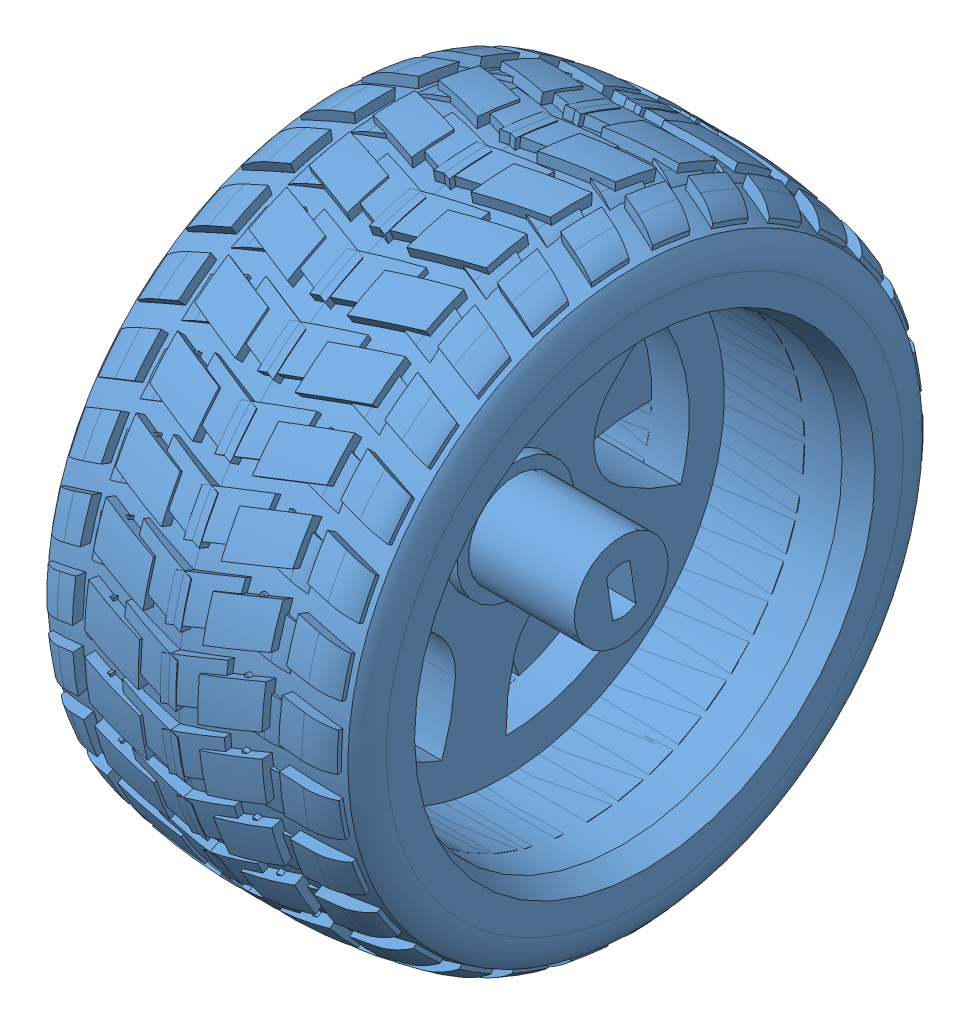
SolidWorks assembly Wheel+motor+shaft+screw, configuration Wheel with L shape. Lengths in mm.
Overall size (34 77.84 77.79).
3 component instances, 2 part files, 8 mates.
Components (placement in the parent):
- motor-1: motor [Default] at (-176.6436 24.9401 31.3103) (suppressed, hidden)
- wheel (scaled)-2: wheel (scaled) [Default] at (-201.6436 24.9401 42.5603) x (1 0 0) z (0 0.988792 0.1493)
- wheel (scaled)-1: wheel (scaled) [Default] at (-205.6436 24.9401 42.5603) x (1 0 0) z (0 -0.988792 -0.1493)
Mates (geometry in assembly coordinates):
- Concentric1: concentric: cylinder of motor-1 through (-189.1436 24.9401 42.5603) axis (1 0 0) radius 2.5; cylinder of wheel (scaled)-2 through (-151.6436 24.9401 42.5603) axis (-1 0 0) radius 2.45
- Width2: width: plane of wheel (scaled)-2 through (-201.6436 24.9401 42.5603) normal (-1 0 0); plane of wheel (scaled)-2 through (-151.6436 24.9401 42.5603) normal (1 0 0); plane of motor-1 through (-189.1436 35.6901 76.3103) normal (-1 0 0); plane of motor-1 through (-164.1436 35.6901 76.3103) normal (1 0 0)
- Concentric2: concentric: cylinder of assembly; cylinder of wheel (scaled)-2 through (-151.6436 24.9401 42.5603) axis (-1 0 0) radius 2.45; cylinder of wheel (scaled)-1 through (-215.6436 24.9401 42.5603) axis (-1 0 0) radius 2.5
- Width3: width: plane of assembly; plane of assembly; plane of wheel (scaled)-2 through (-191.6436 24.7543 43.7913) normal (0 -0.1493 0.988792); plane of wheel (scaled)-2 through (-191.6436 25.126 41.3292) normal (0 0.1493 -0.988792); plane of wheel (scaled)-1 through (-217.6506 22.986 41.0011) normal (0 -0.1493 0.988792); plane of wheel (scaled)-1 through (-217.6506 22.6127 43.473) normal (0 0.1493 -0.988792)
- Distance1: distance = 1.5 mm: plane of assembly; plane of wheel (scaled)-1 through (-193.1436 24.5669 45.0323) normal (1 0 0); plane of wheel (scaled)-2 through (-191.6436 24.9401 42.5603) normal (-1 0 0)
- Coincident1: coincident: axis of motor-1 through (-162.1436 24.9401 58.3103) axis (-1 0 0); axis of ? through (-164.1436 24.9401 58.3103) axis (1 0 0)
- Parallel1: parallel: plane of motor-1 through (-167.1436 35.6901 76.3103) normal (0 0 1); plane of ? through (-164.1436 70.9401 70.8103) normal (0 0 1)
- Coincident2: coincident: plane of motor-1 through (-164.1436 35.6901 76.3103) normal (1 0 0); plane of ? through (-164.1436 40.9401 58.3103) normal (-1 0 0)
